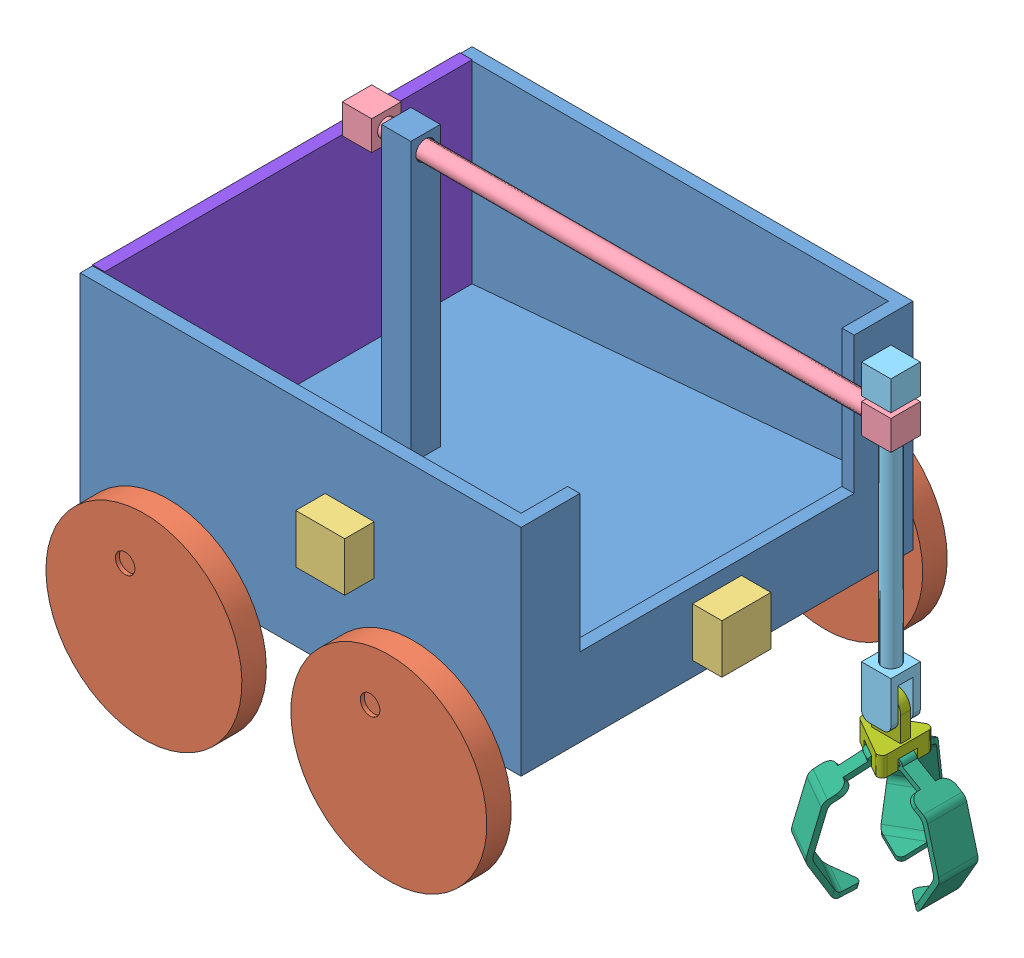
SolidWorks assembly BOT7, configuration Default. Lengths in mm.
Overall size (738.56 510.68 470).
15 component instances, 8 part files, 37 mates.
Components (placement in the parent):
- Base-1: Base [Default] at origin size (450 370 400)
- Wheel-1: Wheel [Default] at (125 -25 -235) size (200 200 105)
- Wheel-2: Wheel [Default] at (-125 -25 -235) size (200 200 105)
- Wheel-3: Wheel [Default] at (-125 -25 235) x (-0.923728 -0.383049 0) z (0 0 -1) size (200 200 105)
- Wheel-4: Wheel [Default] at (125 -25 235) x (-0.923728 -0.383049 0) z (0 0 -1) size (200 200 105)
- Camera-1: Camera [Default] at (50 125 230) x (0 0 -1) z (1 0 0) size (30 50 50)
- Camera-2: Camera [Default] at (50 125 -200) x (0 0 -1) z (1 0 0) size (30 50 50)
- Camera-3: Camera [Default] at (225 40 0) size (30 50 50)
- Extension Pole 1-1: Extension Pole 1 [Default] at (-142.5 305 0) size (560 30 30)
- Extension Pole 2-1: Extension Pole 2 [Default] at (402.5 355 0) x (-1 0 0) z (0 0 1) size (30 315 30)
- Angular Finger-1: Angular Finger [Default] at (399.1062 -46.3881 -5.8782) x (-0.482963 0.258819 -0.836516) z (0.866025 0 -0.5) size (78.27 142.95 40)
- Angular Finger-2: Angular Finger [Default] at (409.2875 -46.3881 0) x (0.965926 0.258819 0) z (0 0 1) size (78.27 142.95 40)
- Angular Finger-3: Angular Finger [Default] at (399.1062 -46.3881 5.8782) x (-0.482963 0.258819 0.836516) z (-0.866025 0 -0.5) size (78.27 142.95 40)
- Triangular Holder-1: Triangular Holder [Default] at (402.5 27.5 0) x (-1 0 0) z (0 0 -1) size (46.96 60 52.68)
- Back-1: Back [Default] at (-225 121.9023 0) size (12.5 198.17 375)
Mates (geometry in assembly coordinates):
- Concentric1: concentric aligned: cylinder of Base-1 through (-125 -25 -132.5736) axis (0 0 -1) radius 15; cylinder of Wheel-2 through (-125 -25 -130) axis (0 0 -1) radius 14
- Distance1: distance = 10 mm anti-aligned: plane of Wheel-2 through (-125 -25 -210) normal (0 0 1); plane of Base-1 through (-225 220 -200) normal (0 0 -1)
- Concentric2: concentric aligned: cylinder of Base-1 through (-125 -25 132.5736) axis (0 0 1) radius 15; cylinder of Wheel-3 through (-125 -25 130) axis (0 0 1) radius 14
- Distance2: distance = 10 mm anti-aligned: plane of Base-1 through (-225 220 200) normal (0 0 1); plane of Wheel-3 through (-125 -25 210) normal (0 0 -1)
- Concentric5: concentric aligned: cylinder of Base-1 through (125 -25 132.5736) axis (0 0 1) radius 15; cylinder of Wheel-4 through (125 -25 130) axis (0 0 1) radius 14
- Distance4: distance = 10 mm anti-aligned: plane of Base-1 through (-225 220 200) normal (0 0 1); plane of Wheel-4 through (125 -25 210) normal (0 0 -1)
- Concentric6: concentric aligned: cylinder of Base-1 through (125 -25 -132.5736) axis (0 0 -1) radius 15; cylinder of Wheel-1 through (125 -25 -130) axis (0 0 -1) radius 14
- Distance5: distance = 10 mm anti-aligned: plane of Base-1 through (-225 220 -200) normal (0 0 -1); plane of Wheel-1 through (125 -25 -210) normal (0 0 1)
- Concentric7: concentric anti-aligned: cylinder of Base-1 through (-102.5 305 0) axis (1 0 0) radius 10; cylinder of Extension Pole 1-1 through (387.5 305 0) axis (-1 0 0) radius 9
- Concentric8: concentric aligned: cylinder of Extension Pole 1-1 through (402.5 261.7157 0) axis (0 1 0) radius 10; cylinder of Extension Pole 2-1 through (402.5 90 0) axis (0 1 0) radius 9
- Coincident5: coincident aligned: plane of Base-1 through (-102.5 320 15) normal (0 0 1); plane of Extension Pole 2-1 through (417.5 325 15) normal (0 0 1)
- Coincident6: coincident anti-aligned: plane of Base-1 through (225 220 -200) normal (1 0 0); plane of Camera-3 through (225 40 0) normal (-1 0 0)
- Distance6: distance = 15 mm aligned: plane of Camera-3 through (255 15 25) normal (0 -1 0); plane of Base-1 through (0 0 0) normal (0 -1 0)
- Distance7: distance = 175 mm aligned: plane of Camera-3 through (255 65 -25) normal (0 0 -1); plane of Base-1 through (-225 220 -200) normal (0 0 -1)
- Coincident9: coincident anti-aligned: plane of Base-1 through (-225 220 200) normal (0 0 1); plane of Camera-1 through (50 125 200) normal (0 0 -1)
- Distance8: distance = 100 mm aligned: plane of Camera-1 through (75 100 200) normal (0 -1 0); plane of Base-1 through (0 0 0) normal (0 -1 0)
- Distance9: distance = 150 mm aligned: plane of Camera-1 through (75 150 200) normal (1 0 0); plane of Base-1 through (225 220 -200) normal (1 0 0)
- Coincident12: coincident anti-aligned: plane of Base-1 through (-225 220 -200) normal (0 0 -1); plane of Camera-2 through (50 125 -200) normal (0 0 1)
- Distance10: distance = 100 mm aligned: plane of Camera-2 through (75 100 -230) normal (0 -1 0); plane of Base-1 through (0 0 0) normal (0 -1 0)
- Distance11: distance = 150 mm aligned: plane of Base-1 through (225 220 -200) normal (1 0 0); plane of Camera-2 through (75 150 -230) normal (1 0 0)
- LimitDistance2: limit distance = 10 mm anti-aligned: plane of Extension Pole 1-1 through (-112.5 305 0) normal (1 0 0); plane of Base-1 through (-102.5 320 -15) normal (-1 0 0)
- LimitDistance3: limit distance = 5 mm anti-aligned: plane of Extension Pole 1-1 through (417.5 320 15) normal (0 1 0); plane of Extension Pole 2-1 through (402.5 325 0) normal (0 -1 0)
- Concentric9: concentric anti-aligned: cylinder of Angular Finger-3 through (378.0192 10.5 2.4019) axis (0.866025 0 0.5) radius 2.5; cylinder of Triangular Holder-1 through (407.6742 10.5 19.5232) axis (-0.866025 0 -0.5) radius 1.5
- Distance12: distance = 2.5 mm anti-aligned: plane of Triangular Holder-1 through (411.1603 17.5 5) normal (-0.866025 0 -0.5); plane of Angular Finger-3 through (405.6014 -46.3881 9.6282) normal (0.866025 0 0.5)
- Concentric10: concentric anti-aligned: cylinder of Angular Finger-1 through (412.6603 10.5 -22.4019) axis (-0.866025 0 0.5) radius 2.5; cylinder of Triangular Holder-1 through (383.0053 10.5 -5.2806) axis (0.866025 0 -0.5) radius 1.5
- Distance13: distance = 2.5 mm anti-aligned: plane of Triangular Holder-1 through (385.1795 17.5 -10) normal (0.866025 0 -0.5); plane of Angular Finger-1 through (392.611 -46.3881 -2.1282) normal (-0.866025 0 0.5)
- Concentric11: concentric anti-aligned: cylinder of Angular Finger-2 through (416.8205 10.5 20) axis (0 0 -1) radius 2.5; cylinder of Triangular Holder-1 through (416.8205 10.5 -14.2426) axis (0 0 1) radius 1.5
- Distance14: distance = 2.5 mm anti-aligned: plane of Triangular Holder-1 through (402.5 17.5 10) normal (0 0 -1); plane of Angular Finger-2 through (409.2875 -46.3881 7.5) normal (0 0 1)
- LimitAngle2: limit planar angle = 2.094395 rad anti-aligned: plane of Triangular Holder-1 through (419.8205 7.5 -30) normal (-0.5 0 -0.866025); plane of Angular Finger-1 through (402.5435 1.7049 -39.9247) normal (-0.25 0.866025 -0.433013)
- LimitAngle3: limit planar angle = 2.094395 rad anti-aligned: plane of Triangular Holder-1 through (419.8205 7.5 30) normal (1 0 0); plane of Angular Finger-2 through (437.0541 1.7049 20) normal (0.5 0.866025 0)
- LimitAngle4: limit planar angle = 2.094395 rad anti-aligned: plane of Triangular Holder-1 through (367.859 7.5 0) normal (-0.5 0 0.866025); plane of Angular Finger-3 through (367.9025 1.7049 19.9247) normal (-0.25 0.866025 0.433013)
- Concentric12: concentric anti-aligned: cylinder of Extension Pole 2-1 through (402.5 52.5 -28.7132) axis (0 0 1) radius 7.5; cylinder of Triangular Holder-1 through (402.5 52.5 27.6274) axis (0 0 -1) radius 8
- Distance16: distance = 2.5 mm anti-aligned: plane of Triangular Holder-1 through (417.5 67.5 -5) normal (0 0 -1); plane of Extension Pole 2-1 through (417.5 80 -7.5) normal (0 0 1)
- LimitAngle5: limit planar angle = 1.570796 rad anti-aligned: plane of Triangular Holder-1 through (402.5 27.5 0) normal (0 1 0); plane of Extension Pole 2-1 through (417.5 40 -15) normal (1 0 0)
- Coincident13: coincident aligned: plane of Base-1 through (-225 220 -200) normal (-1 0 0); plane of Back-1 through (-225 121.9023 0) normal (-1 0 0)
- Coincident14: coincident anti-aligned: plane of Base-1 through (-212.5 60 -187.5) normal (0 0 1); plane of Back-1 through (-212.5 220.9873 -187.5) normal (0 0 -1)
- LimitDistance4: limit distance = 0 mm anti-aligned: plane of Base-1 through (-648.6815 22.8173 187.5) normal (0 1 0); plane of Back-1 through (-212.5 22.8173 187.5) normal (0 -1 0)
